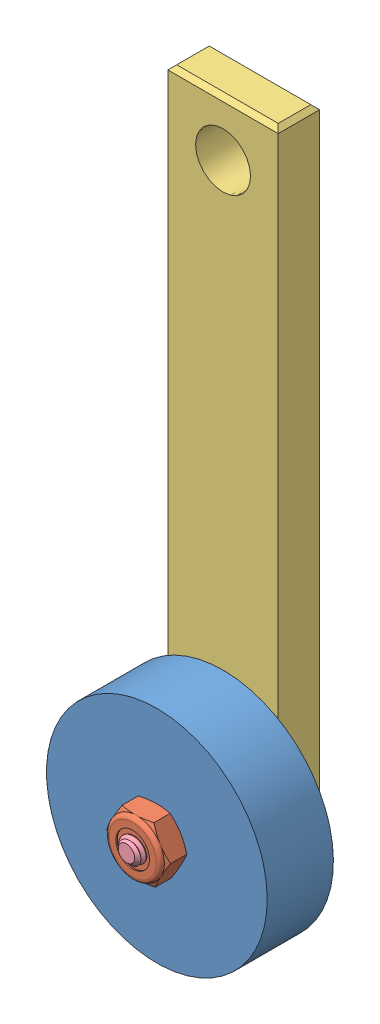
SolidWorks assembly bottom_link_assy, configuration Default. Lengths in mm.
Overall size (31.92 85.81 16.22).
4 component instances, 4 part files, 11 mates.
Components (placement in the parent):
- Mass_blank-1: Mass_blank [Default] at (0 -69.85 4.7625) x (0.9527 0.303914 0) z (0 0 1) size (25.4 25.4 7.62)
- 4_40_THIN_LOCKNUT_90633A005-1: 4_40_THIN_LOCKNUT_90633A005 [90633A005] at (0 -69.85 12.3825) x (0.853828 0.520556 0) z (0.520556 -0.853828 0) size (6.35 2.86 7.33)
- bottom_link-1: bottom_link [Default] at (0 -6.35 4.7625) x (0 1 0) z (-1 0 0) size (76.2 4.76 12.7)
- 4_40-625-countersunk-stainless-92210a112-1: 4_40-625-countersunk-stainless-92210a112 [92210A112] at (0 -69.85 0) x (-0.923728 -0.383049 0) z (0 0 -1) size (6.48 6.48 16.22)
Mates (geometry in assembly coordinates):
- Coincident40: coincident anti-aligned: plane of Mass_blank-1 through (0 -63.5 12.3825) normal (0 0 1); plane of 4_40_THIN_LOCKNUT_90633A005-1 through (-5.5736 -60.4573 12.3825) normal (0 0 -1)
- Concentric30: concentric aligned: cylinder of Mass_blank-1 through (0 -63.5 12.3825) axis (0 0 -1) radius 12.7; cylinder of 4_40_THIN_LOCKNUT_90633A005-1 through (0 -63.5 16.4306) axis (0 0 -1) radius 1.9297
- Concentric31: concentric anti-aligned: cylinder of Mass_blank-1 through (0 -63.5 12.3825) axis (0 0 1) radius 1.632; cylinder of bottom_link-1 through (0 -63.5 0) axis (0 0 -1) radius 1.632
- Coincident41: coincident anti-aligned: plane of bottom_link-1 through (0 0 4.7625) normal (0 0 1); plane of Mass_blank-1 through (0 -63.5 4.7625) normal (0 0 -1)
- Coincident42: coincident anti-aligned: plane of bottom_link-1 through (0 0 0) normal (0 0 -1); plane of ? through (1.8032 -65.5164 0) normal (0 0 1)
- Concentric32: concentric aligned: cylinder of bottom_link-1 through (0 -63.5 0) axis (0 0 -1) radius 1.632; cylinder of ? through (0 -63.5 -1.4986) axis (0 0 -1) radius 2.7051
- Symmetric1: symmetric aligned: plane of bottom_link-1 through (-6.35 0 0) normal (-1 0 0); plane of bottom_link-1 through (6.35 0 0) normal (1 0 0); plane of assembly through (0 0 0) normal (1 0 0)
- Coincident43: coincident anti-aligned: plane of bottom_link-1 through (0 0 0) normal (0 0 -1); plane of assembly through (0 0 0) normal (0 0 1)
- Coincident44: coincident aligned: plane of bottom_link-1 through (0 0 0) normal (0 1 0); plane of assembly
- Concentric33: concentric aligned: cylinder of bottom_link-1 through (0 -63.5 0) axis (0 0 -1) radius 1.632; cylinder of 4_40-625-countersunk-stainless-92210a112-1 through (0 -63.5 0) axis (0 0 -1) radius 3.2385
- Coincident45: coincident aligned: plane of bottom_link-1 through (0 0 0) normal (0 0 -1); plane of 4_40-625-countersunk-stainless-92210a112-1 through (0.5448 -64.8139 0) normal (0 0 -1)
